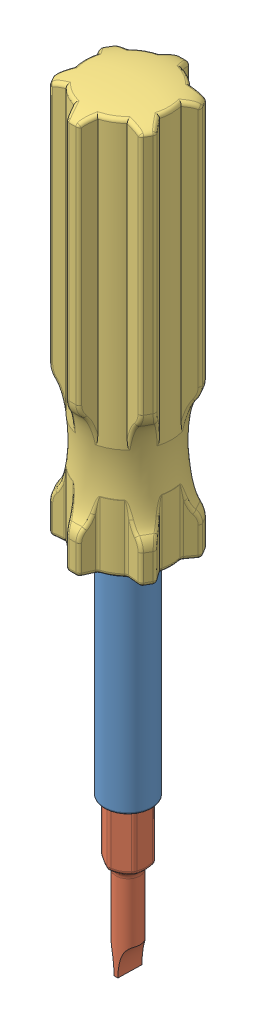
SolidWorks assembly SD, configuration Default. Lengths in mm.
Overall size (28 194.22 28.48).
3 component instances, 3 part files, 4 mates.
Components (placement in the parent):
- sd_shaft-1: sd_shaft [Default] at (35.9379 15.0407 122.2608) x (-0.281168 0 0.959658) z (-0.959658 0 -0.281168) size (12 110 12)
- sd_bit-1: sd_bit [Default] at (31.6089 31.0407 122.1654) x (0.022023 0 -0.999757) z (-0.999757 0 -0.022023) size (9.69 78.22 8.66)
- sd_base-2: sd_base [Default] at (35.9379 70.0407 122.2608) size (28 101 28.48)
Mates (geometry in assembly coordinates):
- Concentric1: concentric: cylinder of sd_shaft-1 through (35.9379 125.0407 122.2608) axis (0 -1 0) radius 5; circle of sd_bit-1
- Concentric2: concentric: circle of sd_shaft-1; circle of sd_base-2
- Coincident1: coincident: plane of sd_shaft-1 through (35.9379 125.0407 122.2608) normal (0 1 0); plane of sd_base-2 through (35.9379 125.0407 122.2608) normal (0 -1 0)
- Distance1: distance = 70 mm: plane of sd_base-2 through (35.9379 125.0407 122.2608) normal (0 -1 0); plane of sd_bit-1 through (35.9379 55.0407 122.2608) normal (0 1 0)
